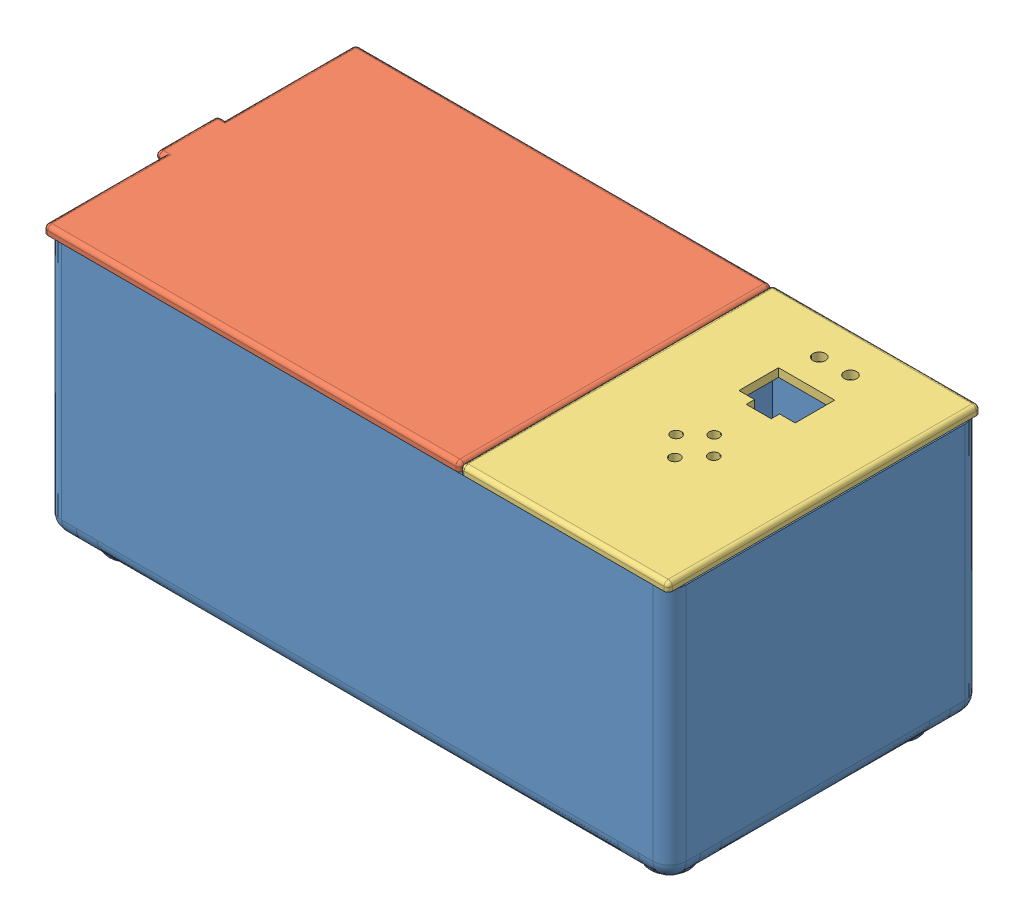
SolidWorks assembly Assembly Final, configuration Default. Lengths in mm.
Overall size (304.25 135 150).
3 component instances, 3 part files, 3 mates.
Components (placement in the parent):
- enclosure-1: enclosure [Default] at (-210.7264 -85.9617 188.3117) size (300 131 150)
- top slider-2: top slider [Default] at (-217.8465 37.0383 93.6002) x (-1 0 0) z (0 0 -1) size (203.54 4 150)
- displaypart-2: displaypart [Default] at (-11.4095 37.0383 188.3117) size (100 4 150)
Mates (geometry in assembly coordinates):
- Coincident1: coincident aligned: line of enclosure-1 through (-202.7264 37.0383 188.3117) axis (1 0 0); line of displaypart-2 through (-9.4095 37.0383 188.3117) axis (1 0 0)
- Coincident2: coincident anti-aligned: line of enclosure-1 through (-11.4095 37.0383 49.3117) axis (0 0 1); line of displaypart-2 through (-11.4095 37.0383 186.3117) axis (0 0 -1)
- Coincident3: coincident aligned: line of enclosure-1 through (-202.7264 37.0383 188.3117) axis (1 0 0); line of top slider-2 through (-209.4363 37.0383 188.3117) axis (1 0 0)
